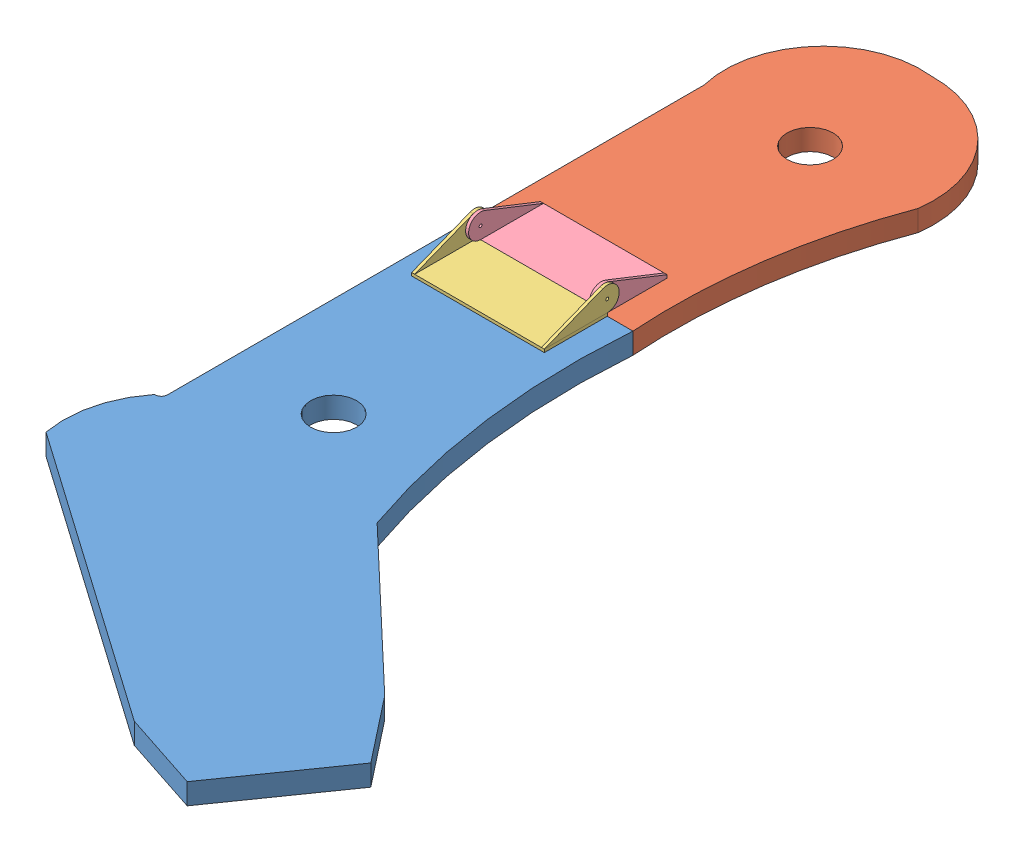
SolidWorks assembly LiftArmPaddle, configuration Default. Lengths in mm.
Overall size (238.84 25.4 521.17).
4 component instances, 4 part files, 7 mates.
Components (placement in the parent):
- liftArmLower-1: liftArmLower [Default] at (0.282 201.1124 91.9918) size (238.84 11.11 324.8)
- liftArmUpper-1: liftArmUpper [Default] at (9.4101 201.1219 -39.7721) x (1 0 0) z (0 -0.000072 1) size (115.4 11.11 196.36)
- hingPart-1: hingPart [Default] at (-36.0629 212.2249 124.9135) x (0 0 -1) z (1 0 0) size (39.69 14.29 70.3)
- hingPartTwo-1: hingPartTwo [Default] at (49.3335 212.2268 66.7586) x (0 0.000072 -1) z (1 0 0) size (39.69 14.29 67.07)
Mates (geometry in assembly coordinates):
- Coincident2: coincident aligned: circle of hingPart-1; circle of hingPartTwo-1
- Coincident3: coincident anti-aligned: plane of liftArmLower-1 through (-49.9227 212.2249 244.5902) normal (0 1 0); plane of hingPart-1 through (-36.0629 212.2249 124.9135) normal (0 -1 0)
- Coincident4: coincident aligned: line of liftArmLower-1 through (47.3117 212.2249 91.9918) axis (-1 0 0); line of hingPart-1 through (33.7123 212.2249 91.9918) axis (-1 0 0)
- Coincident5: coincident aligned: line of liftArmUpper-1 through (-46.7477 212.2249 91.9912) axis (1 0 0); line of hingPartTwo-1 through (-35.0002 212.2249 91.9912) axis (1 0 0)
- Coincident6: coincident anti-aligned: plane of liftArmUpper-1 through (3.7577 212.2354 -52.3296) normal (0 1 0.000072); plane of hingPartTwo-1 through (49.3335 212.2268 66.7586) normal (0 -1 -0.000072)
- Coincident8: coincident aligned: plane of liftArmLower-1 through (-46.7477 212.2249 91.9918) normal (-1 0 0); plane of liftArmUpper-1 through (-46.7477 212.2344 -39.7713) normal (-1 0 0)
- Distance1: distance = 10.16 mm aligned: plane of hingPart-1 through (-36.5877 213.8124 125.3293) normal (-1 0 0); plane of liftArmLower-1 through (-46.7477 212.2249 91.9918) normal (-1 0 0)
